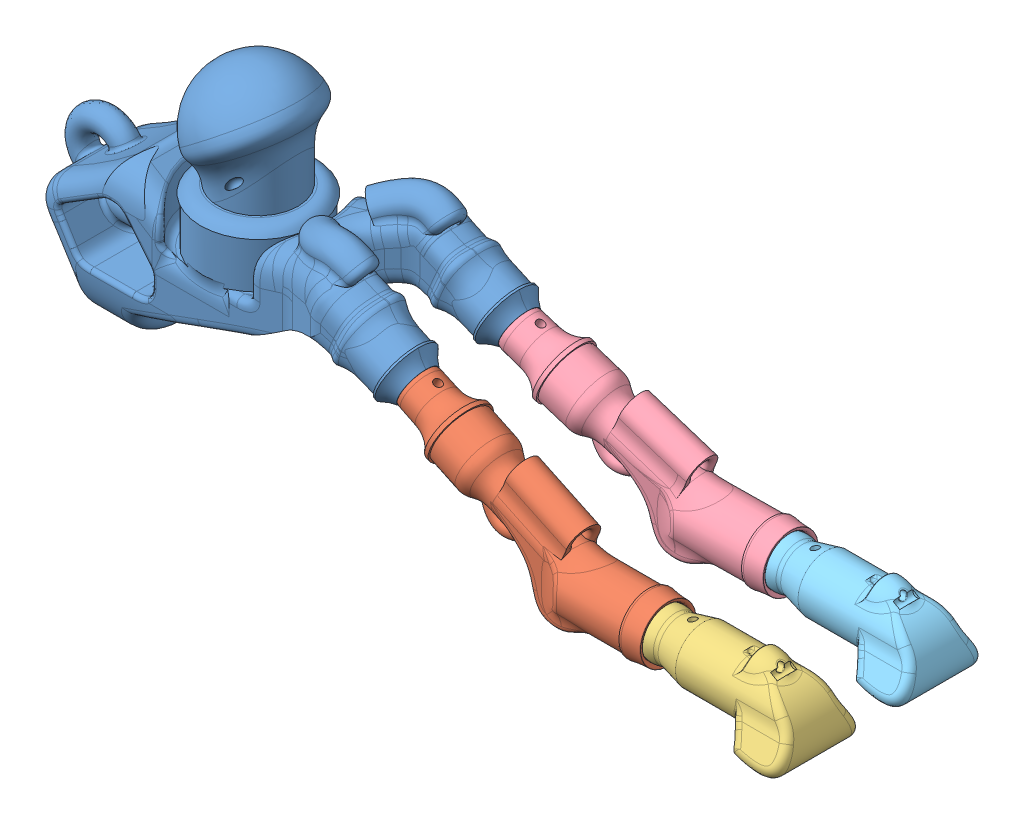
SolidWorks assembly 05_01_Foot, configuration Default. Lengths in mm.
Overall size (260.5 96.31 79.33).
5 component instances, 5 part files, 4 mates.
Components (placement in the parent):
- Talus - New201810205-1: Talus - New201810205 [Default] at origin size (131.32 86.19 51)
- Metatarsals-1: Metatarsals [Default] at (104.0952 -44.3034 18.1531) x (-0.929116 0.366544 -0.048875) z (0.042994 -0.024198 -0.998782) size (95.04 30.95 38.02)
- Phalanges-1: Phalanges [Default] at (172.2396 -55.1541 19.5999) size (57.16 24.44 28.69)
- Metatarsals - Left side-1: Metatarsals - Left side [Default] at (104.1326 -44.2161 -17.9587) x (-0.930097 0.364252 0.047332) z (-0.050841 -0.000045 -0.998707) size (95.04 30.95 38.02)
- Phalanges - Left side-1: Phalanges - Left side [Default] at (172.3053 -54.9301 -19.5095) size (57.16 24.44 28.69)
Mates (geometry in assembly coordinates):
- Concentric1: concentric: sphere of Metatarsals-1; sphere of Talus - New201810205-1
- Concentric2: concentric: sphere of Phalanges-1; sphere of Metatarsals-1
- Concentric3: concentric: sphere of Talus - New201810205-1; sphere of Metatarsals - Left side-1
- Concentric4: concentric: sphere of Phalanges - Left side-1; sphere of Metatarsals - Left side-1
